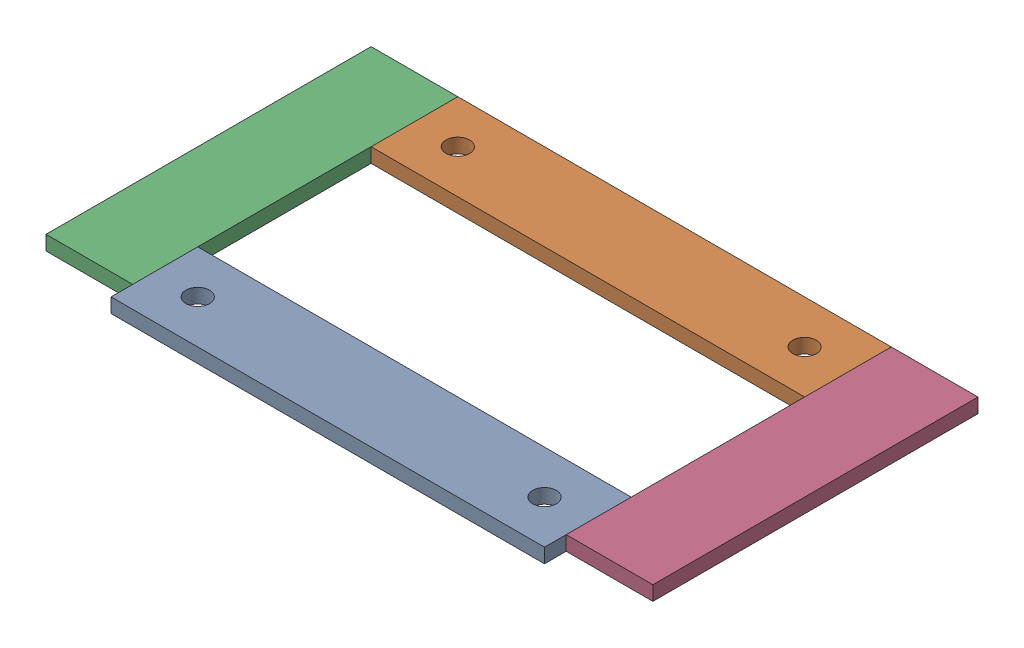
SolidWorks assembly 01-059-00-0, configuration Default. Lengths in mm.
Overall size (533.4 12.7 304.8).
4 component instances, 2 part files, 0 mates.
Components (placement in the parent):
- 01-057-00-0-1: 01-057-00-0 [Default] at origin size (381 12.7 76.2)
- 01-057-00-0-2: 01-057-00-0 [Default] at (0 0 -228.6) size (381 12.7 76.2)
- 01-058-00-0-1: 01-058-00-0 [Default] at (-76.2 0 -304.8) x (0 0 1) z (-1 0 0) size (285.75 12.7 76.2)
- 01-058-00-0-2: 01-058-00-0 [Default] at (381 0 -304.8) x (0 0 1) z (-1 0 0) size (285.75 12.7 76.2)
